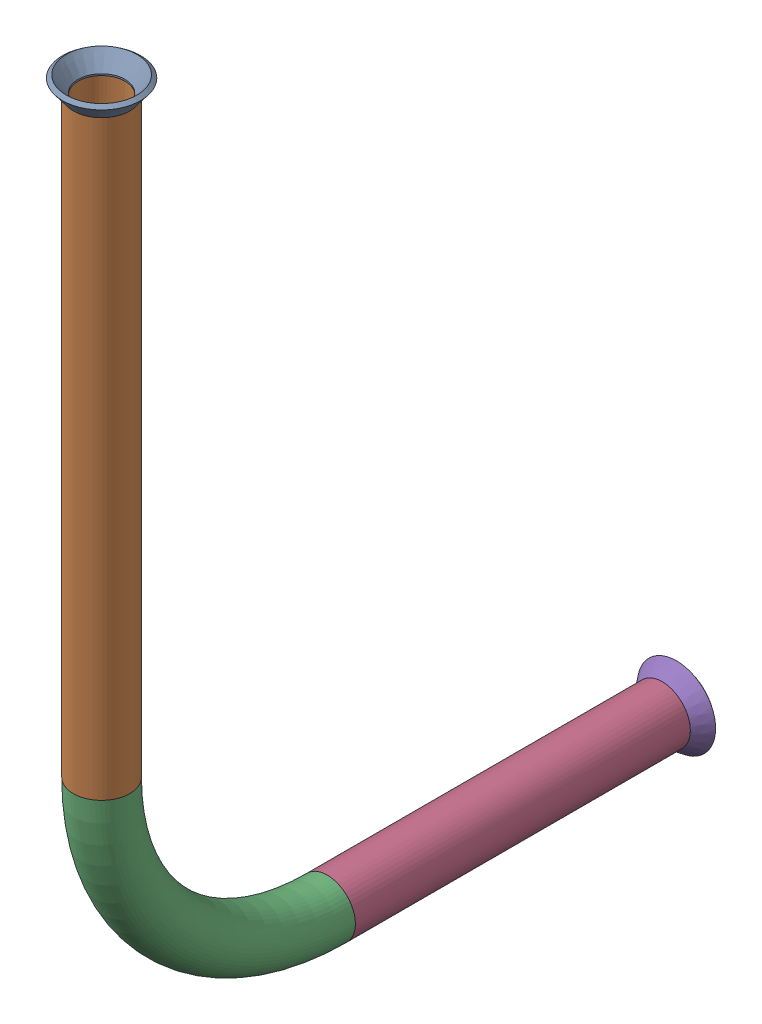
SolidWorks assembly Pipe 22, configuration Default. Lengths in mm.
Overall size (17.59 196.62 138.92).
3 component instances, 2 part files, 8 mates.
Components (placement in the parent):
- Flared pipe end - .5 inch-1: Flared pipe end - .5 inch [Default<As Machined>] at (83.1415 -188.1312 279.3782) x (1 0 0.00017) z (0 1 0) size (17.59 17.59 3.89)
- part 7-2: part 7 [Default<As Machined>] at (83.1415 821.6166 589.5083) x (1 0 0) z (0 0 -1) size (12.7 190.28 132.58)
- Flared pipe end - .5 inch-3: Flared pipe end - .5 inch [Default<As Machined>] at (83.1415 -372.0641 153.1433) x (1 0 0) z (0 0 -1) size (17.59 17.59 3.89)
Mates (geometry in assembly coordinates):
- Coincident1032: coincident: plane of ? through (0 -188.1312 291.3922) normal (0 1 0); plane of Flared pipe end - .5 inch-1 through (0.0009 -188.1312 286.109) normal (0 -1 0)
- Concentric658: concentric: circle of ?; circle of Flared pipe end - .5 inch-1
- Coincident1033: coincident: plane of ? through (0 -276.3764 360.7276) normal (0 0 1); plane of ? through (0.0009 -271.0932 360.7276) normal (0 0 -1)
- Concentric659: concentric: circle of ?; circle of ?
- Coincident1146: coincident: plane of Flared pipe end - .5 inch-1 through (83.1424 -188.1312 274.095) normal (0 -1 0); plane of part 7-2 through (83.1415 -188.1312 279.3782) normal (0 1 0)
- Coincident1147: coincident: circle of Flared pipe end - .5 inch-1; circle of part 7-2
- Coincident1149: coincident: plane of part 7-2 through (83.1415 -372.0641 153.1433) normal (0 0 -1); plane of Flared pipe end - .5 inch-3 through (83.1415 -377.3473 153.1433) normal (0 0 1)
- Concentric698: concentric: cylinder of part 7-2 through (83.1415 -372.0641 153.1433) axis (0 0 1) radius 5.2832; circle of Flared pipe end - .5 inch-3
